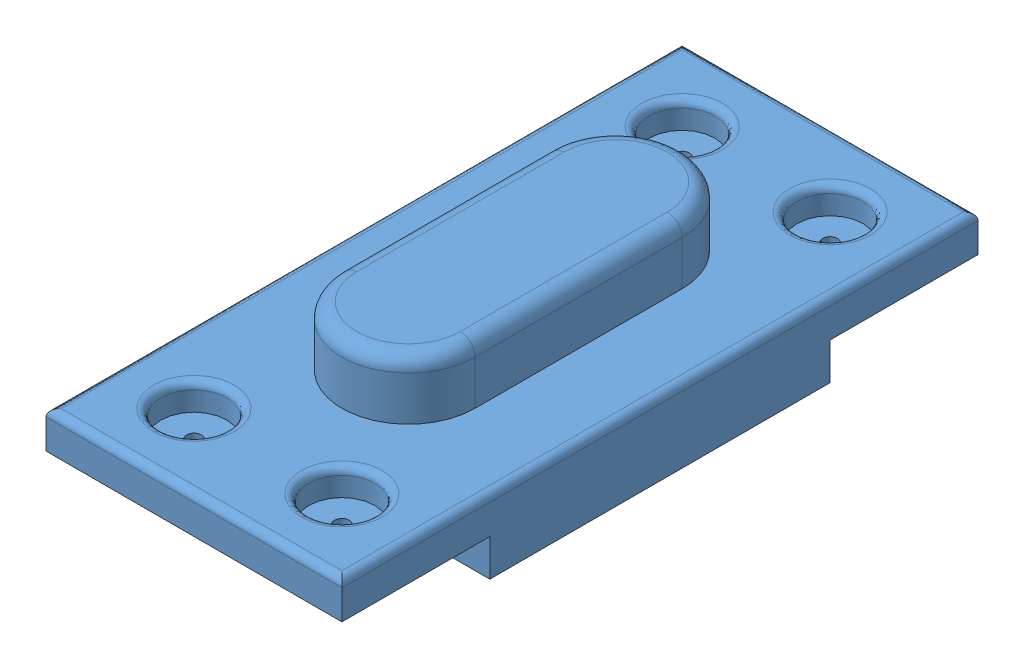
SolidWorks assembly Assem1, configuration Default. Lengths in mm.
Overall size (20 9 43).
10 component instances, 5 part files, 15 mates.
Components (placement in the parent):
- holder-1: holder [Default] at (-46.6361 21.9173 23.4756) size (20 9 43)
- Leg-1: Leg [Default] at (-46.6361 19.4173 23.4756) x (-1 0 0) z (0 -1 0) size (20 42.77 32.21) (hidden)
- Leg-2: Leg [Default] at (119.3639 19.4173 23.4756) x (1 0 0) z (0 -1 0) size (20 42.77 32.21) (hidden)
- holder-2: holder [Default] at (-46.6361 21.9173 23.4756) x (-1 0 0) z (0 0 -1) size (20 9 43) (hidden)
- Leg-3: Leg [Default] at (-212.6361 19.4173 23.4756) x (-1 0 0) z (0 -1 0) size (20 42.77 32.21) (hidden)
- Leg-4: Leg [Default] at (-46.6361 19.4173 23.4756) x (1 0 0) z (0 -1 0) size (20 42.77 32.21) (hidden)
- Middle_mount-1: Middle_mount [Default] at origin size (179.5 3.25 9.5) (hidden)
  - Copy of Copy of Copy of Part3^Middle_mount-1: Copy of Copy of Copy of Part3^Middle_mount [Default] at (-46.6361 20.9173 23.4756) x (-1 0 0) z (0 -1 0) size (179.5 9.5 3.25) (virtual)
- Part4-1: Part4 [Default] at origin (hidden)
- Part5-1: Part5 [Default] at origin (hidden)
Mates (geometry in assembly coordinates):
- InPlace1: in place: plane of holder-1 through (16.0561 19.4173 1.9756) normal (0 -1 0); plane of ? through (0 19.4173 0) normal (0 -1 0); moOrthogonalPlaneRef_w of holder-1 through (16.0561 19.4173 1.9756) normal (0 -1 0); plane of ? through (0 19.4173 0) normal (0 0 -1); plane of holder-1 through (16.0561 19.4173 1.9756) normal (0 -1 0); plane of ? through (0 19.4173 0) normal (-1 0 0); plane of holder-1 through (16.0561 19.4173 1.9756) normal (0 -1 0); unknown of Leg-1
- Coincident1: coincident aligned: plane of holder-1; plane of Leg-1
- Coincident2: coincident aligned: moOrthogonalPlaneRef_w of holder-1 through (-46.6361 19.4173 23.4756) normal (0 0 -1); plane of Leg-1 through (-46.6361 19.4173 23.4756) normal (0 0 -1)
- Coincident3: coincident anti-aligned: moOrthogonalPlaneRef_w of holder-1 through (-46.6361 19.4173 23.4756) normal (1 0 0); plane of Leg-1 through (-46.6361 19.4173 23.4756) normal (-1 0 0)
- Coincident4: coincident anti-aligned: plane of holder-1 through (16.0561 19.4173 44.9756) normal (0 -1 0); plane of Leg-2 through (119.3639 19.4173 23.4756) normal (0 1 0)
- Coincident5: coincident anti-aligned: plane of holder-1 through (16.0561 16.9173 34.9756) normal (0 0 1); plane of Leg-2 through (46.3639 14.4173 34.9756) normal (0 0 -1)
- Coincident6: coincident aligned: plane of holder-1 through (26.3639 16.9173 23.4756) normal (-1 0 0); plane of Leg-2 through (26.3639 14.4173 34.9756) normal (-1 0 0)
- Coincident9: coincident aligned: circle of holder-1; circle of holder-2
- Coincident10: coincident anti-aligned: line of holder-1 through (-134.6361 21.9173 30.4756) axis (0 0 -1); line of holder-2 through (-134.6361 21.9173 16.4756) axis (0 0 1)
- Coincident11: coincident anti-aligned: plane of holder-2 through (-109.3284 19.4173 44.9756) normal (0 -1 0); plane of Leg-4 through (-46.6361 19.4173 23.4756) normal (0 1 0)
- Coincident12: coincident anti-aligned: plane of holder-2 through (-109.3284 16.9173 34.9756) normal (0 0 1); plane of Leg-4 through (-119.6361 14.4173 34.9756) normal (0 0 -1)
- Coincident13: coincident aligned: plane of holder-2 through (-139.6361 16.9173 23.4756) normal (-1 0 0); plane of Leg-4 through (-139.6361 14.4173 34.9756) normal (-1 0 0)
- Coincident14: coincident aligned: plane of holder-2 through (-139.6361 16.9173 23.4756) normal (-1 0 0); plane of Leg-3 through (-139.6361 14.4173 11.9756) normal (-1 0 0)
- Coincident15: coincident anti-aligned: plane of holder-2 through (-109.3284 19.4173 1.9756) normal (0 -1 0); plane of Leg-3 through (-212.6361 19.4173 23.4756) normal (0 1 0)
- Coincident16: coincident anti-aligned: plane of holder-2 through (-109.3284 16.9173 11.9756) normal (0 0 -1); plane of Leg-3 through (-139.6361 14.4173 11.9756) normal (0 0 1)
